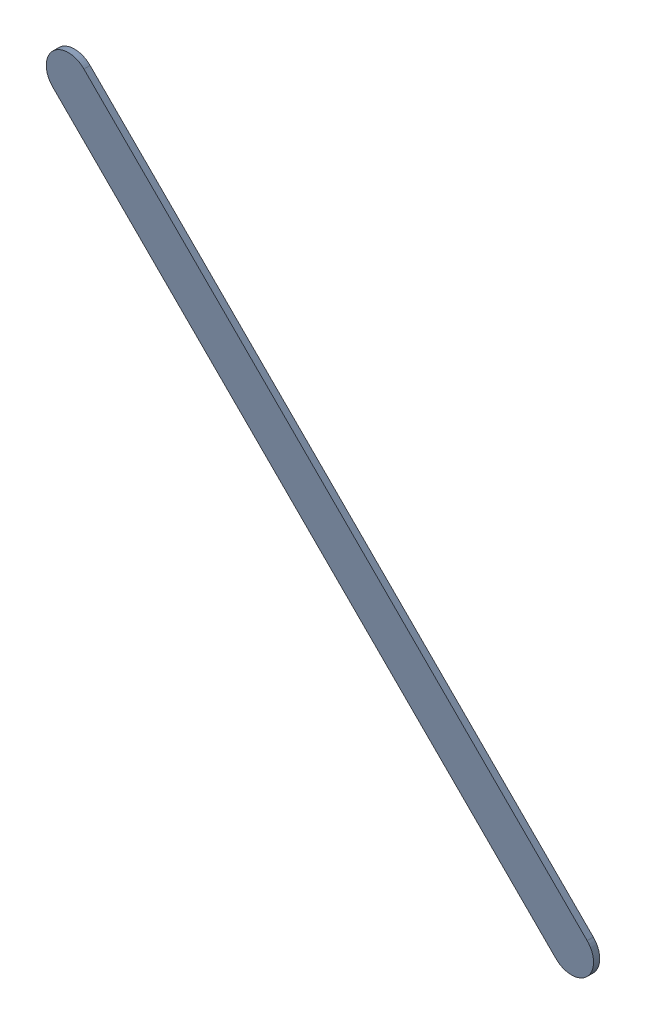
SolidWorks assembly Track (19mm,53.5mm)(21.9mm,50.6mm) on Top Layer, configuration Predeterminado. Lengths in mm.
Overall size (3.15 3.15 0.04).
2 component instances, 1 part files, 0 mates.
Components (placement in the parent):
- Track (19mm,53.5mm)(21.9mm,50.6mm) on Top Layer-1-1: Track (19mm,53.5mm)(21.9mm,50.6mm) on Top Layer-1 [Predeterminado] at (-68.317 -44.187 -0.0457) size (3.15 3.15 0.04)
  - Track (19mm,53.5mm)(21.9mm,50.6mm) on Top Layer-Part-1-1: Track (19mm,53.5mm)(21.9mm,50.6mm) on Top Layer-Part-1 [Predeterminado] at origin size (3.15 3.15 0.04)
